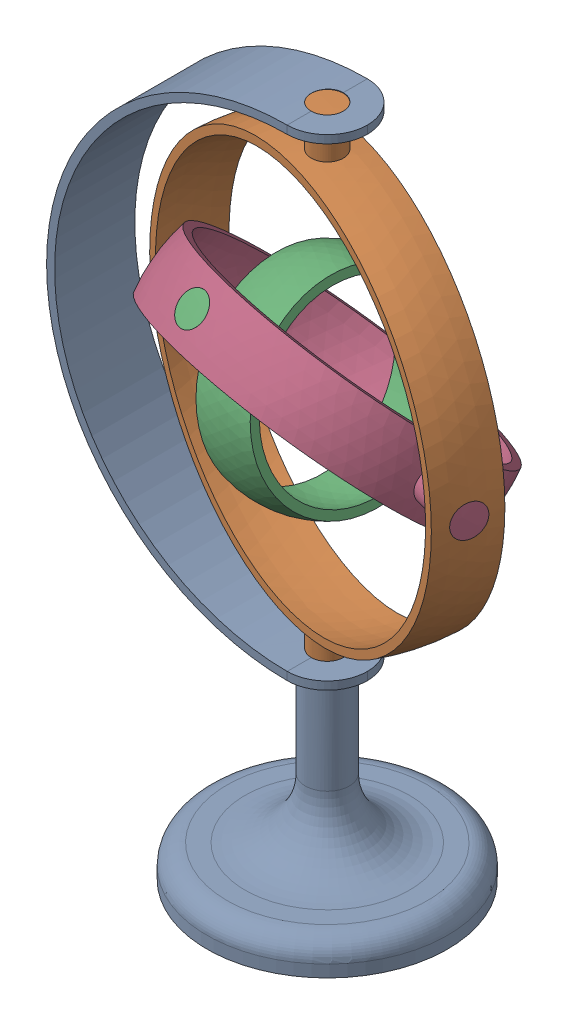
SolidWorks assembly Assem1, configuration Default. Lengths in mm.
Overall size (116.73 168 89.51).
4 component instances, 4 part files, 8 mates.
Components (placement in the parent):
- part4-1: part4 [Default] at (-16.7369 23.1753 17.3074) size (90 168 60)
- part1-2: part1 [Default] at (-16.7369 23.1753 17.3074) x (0.966625 0 0.256194) z (0 -1 0) size (100 15 120)
- part 3-1: part 3 [Default] at (-16.7369 23.1753 17.3074) x (0.086664 -0.713312 0.695468) z (-0.189358 0.673573 0.714452) size (50 15 75)
- Part2-3: Part2 [Default] at (-16.7369 23.1753 17.3074) x (-0.189358 0.673573 0.714452) z (-0.966625 0 -0.256194) size (75 15 100)
Mates (geometry in assembly coordinates):
- Concentric3: concentric anti-aligned: cylinder of part4-1 through (-16.7369 -36.8247 17.3074) axis (0 1 0) radius 4; circle of part1-2
- Concentric4: concentric: cylinder of part4-1 through (-16.7369 23.1753 27.3074) axis (0 0 -1) radius 60; sphere of part1-2
- Concentric29: concentric: sphere of part1-2; sphere of Part2-3
- Concentric30: concentric: sphere of part1-2; sphere of Part2-3
- Concentric33: concentric aligned: cylinder of part 3-1 through (-12.0028 6.3353 -0.5546) axis (-0.189358 0.673573 0.714452) radius 4; cylinder of Part2-3 through (-9.636 -2.0837 -9.4845) axis (-0.189358 0.673573 0.714452) radius 4
- Concentric34: concentric: sphere of part 3-1; sphere of Part2-3
- Concentric35: concentric: sphere of Part2-3; sphere of part1-2
- Concentric37: concentric anti-aligned: circle of part1-2; circle of Part2-3
